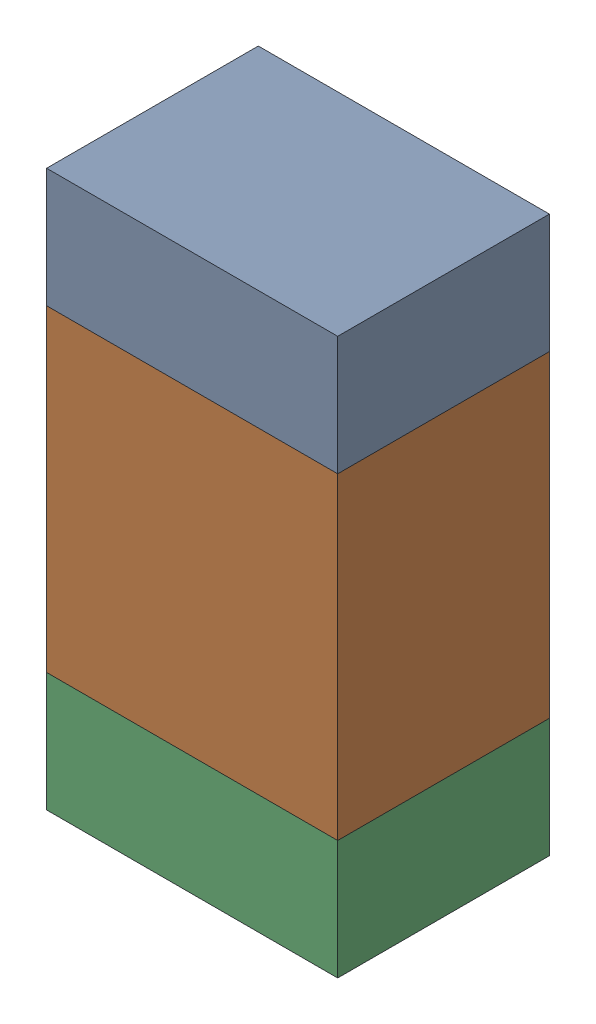
SolidWorks assembly R111_1PCB, configuration Default. Lengths in mm.
Overall size (0.55 1.05 0.4).
6 component instances, 2 part files, 0 mates.
Components (placement in the parent):
- 846483288-1: 846483288 [Default] at (115.7001 114.0124 0) size (0.55 0.22 0.4)
  - Extruded_12-1: Extruded_12 [Default] at origin size (0.55 0.22 0.4)
- 846483424-1: 846483424 [Default] at (115.7001 113.5999 0) size (0.55 0.6 0.4)
  - Extruded_13-1: Extruded_13 [Default] at origin size (0.55 0.6 0.4)
- 846483288-2: 846483288 [Default] at (115.7001 113.1874 0) size (0.55 0.22 0.4)
  - Extruded_12-1: Extruded_12 [Default] at origin size (0.55 0.22 0.4)
